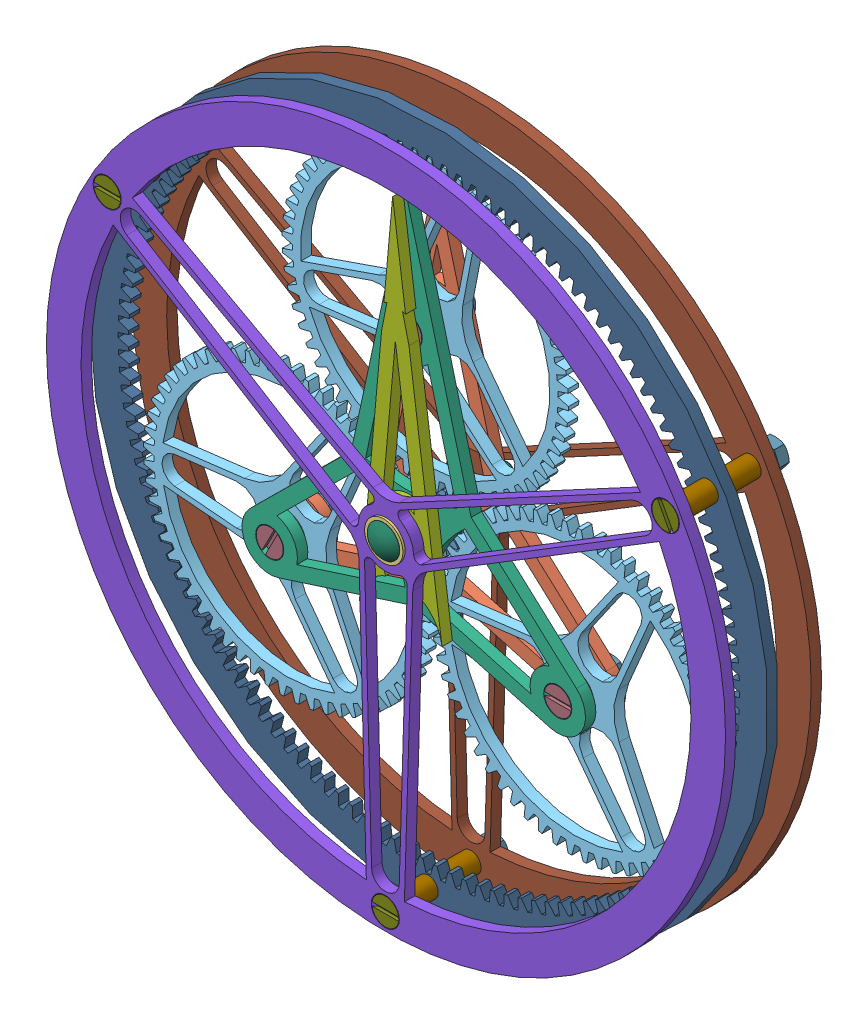
SolidWorks assembly FINAL CLOCK ASSEMBLY, configuration Default. Lengths in mm.
Overall size (311.76 311.76 60.58).
55 component instances, 16 part files, 120 mates.
Components (placement in the parent):
- SUN GEAR - HOUR-1: SUN GEAR - HOUR [Inch - Spur gear 12DP 12T 14.5PA .1875FW ---S12N3.0H2.0L0.25N] at (-10.4963 -0.1494 4.7625) x (0 0 -1) z (-0.958685 -0.284468 0) size (4.76 28.9 28.9)
- HOUR HAND - REAR-1: HOUR HAND - REAR [Default] at (-10.4963 -0.1494 -1.1811) x (-0.021998 0.999758 0) z (0 0 1) size (181.56 157.38 4.76)
- FLANGE BEARING-1: FLANGE BEARING [57155K324] at (-10.4963 -0.1494 -4.4704) size (17.53 17.53 4.98)
- Hi Collar LW 0.25-1: Hi Collar LW 0.25 [Hi Collar LW 0.25] at (-10.4963 -0.1494 -1.9812) x (0 0 -1) z (1 0 0) size (1.98 9.22 9.21)
- PLANET GEAR - HOUR-1: PLANET GEAR - HOUR [Inch - Spur gear 12DP 60T 14.5PA .1875FW ---S60N3.0H2.0L0.625N] at (-75.6334 -39.6919 0) x (0 0 1) z (0.019031 -0.999819 0) size (4.76 131.13 131.13)
- FLANGE BEARING-2: FLANGE BEARING [57155K324] at (-75.6334 -39.6919 3.2893) x (0.381849 -0.924225 0) z (0 0 -1) size (17.53 17.53 4.98)
- Hi Collar LW 0.25-2: Hi Collar LW 0.25 [Hi Collar LW 0.25] at (-75.6334 -39.6919 0.8001) x (0 0 1) z (-1 0 0) size (1.98 9.22 9.21)
- PLANET GEAR - HOUR-2: PLANET GEAR - HOUR [Inch - Spur gear 12DP 60T 14.5PA .1875FW ---S60N3.0H2.0L0.625N] at (-12.1726 76.0322 0) x (0 0 1) z (0.228279 -0.973596 0) size (4.76 131.13 131.13)
- FLANGE BEARING-3: FLANGE BEARING [57155K324] at (-12.1726 76.0322 3.2893) x (0.381849 -0.924225 0) z (0 0 -1) size (17.53 17.53 4.98)
- Hi Collar LW 0.25-3: Hi Collar LW 0.25 [Hi Collar LW 0.25] at (-12.1726 76.0322 0.8001) x (0 0 1) z (-1 0 0) size (1.98 9.22 9.21)
- PLANET GEAR - HOUR-4: PLANET GEAR - HOUR [Inch - Spur gear 12DP 60T 14.5PA .1875FW ---S60N3.0H2.0L0.625N] at (56.317 -36.7885 0) x (0 0 1) z (0.018854 -0.999822 0) size (4.76 131.13 131.13)
- FLANGE BEARING-5: FLANGE BEARING [57155K324] at (56.317 -36.7885 3.2893) x (0.381849 -0.924225 0) z (0 0 -1) size (17.53 17.53 4.98)
- Hi Collar LW 0.25-4: Hi Collar LW 0.25 [Hi Collar LW 0.25] at (56.317 -36.7885 0.8001) x (0 0 1) z (-1 0 0) size (1.98 9.22 9.21)
- HOUR HAND - FRONT-1: HOUR HAND - FRONT [Default] at (-10.4963 -0.1494 12.5222) x (-0.021998 0.999758 0) z (0 0 1) size (181.56 157.38 4.76)
- FLANGE BEARING-6: FLANGE BEARING [57155K324] at (-10.4963 -0.1494 9.2329) size (17.53 17.53 4.98)
- Hi Collar LW 0.25-5: Hi Collar LW 0.25 [Hi Collar LW 0.25] at (-10.4963 -0.1494 6.7437) x (0 0 1) z (-1 0 0) size (1.98 9.22 9.21)
- Hi Collar LW 0.25-6: Hi Collar LW 0.25 [Hi Collar LW 0.25] at (-75.6334 -39.6919 5.7785) x (0 0 -1) z (1 0 0) size (1.98 9.22 9.21)
- Hi Collar LW 0.25-7: Hi Collar LW 0.25 [Hi Collar LW 0.25] at (-12.1726 76.0322 5.7785) x (0 0 -1) z (1 0 0) size (1.98 9.22 9.21)
- Hi Collar LW 0.25-8: Hi Collar LW 0.25 [Hi Collar LW 0.25] at (56.317 -36.7885 5.7785) x (0 0 -1) z (1 0 0) size (1.98 9.22 9.21)
- Hi Collar LW 0.25-9: Hi Collar LW 0.25 [Hi Collar LW 0.25] at (-10.4963 -0.1494 11.7221) x (0 0 -1) z (1 0 0) size (1.98 9.22 9.21)
- MINUTE HAND-1: MINUTE HAND [Default] at (-10.4963 -0.1494 13.7033) x (-0.021988 0.999758 0) z (0 0 -1) size (167.69 37.86 4.76)
- FRONT FRAME-1: FRONT FRAME [Default] at (-10.4963 -0.1494 24.4094) x (-0.999998 0.001964 0) z (0 0 1) size (311.15 311.15 4.76)
- FLANGE BEARING-7: FLANGE BEARING [57155K324] at (-10.4963 -0.1494 22.9362) x (0.923728 0.383049 0) z (0 0 -1) size (17.53 17.53 4.98)
- Hi Collar LW 0.25-10: Hi Collar LW 0.25 [Hi Collar LW 0.25] at (-10.4963 -0.1494 20.447) x (0 0 1) z (-1 0 0) size (1.98 9.22 9.21)
- STAND OFF - FRONT FRAME-1: STAND OFF - FRONT FRAME [Default] at (-10.7863 -147.7866 4.7879) x (0.923728 0.383049 0) z (0 0 -1) size (9.22 9.22 14.86)
- STAND OFF - FRONT FRAME-2: STAND OFF - FRONT FRAME [Default] at (-138.2089 73.9203 4.7879) x (0.923728 0.383049 0) z (0 0 -1) size (9.22 9.22 14.86)
- STAND OFF - FRONT FRAME-3: STAND OFF - FRONT FRAME [Default] at (117.5062 73.4181 4.7879) x (0.923728 0.383049 0) z (0 0 -1) size (9.22 9.22 14.86)
- RING GEAR - HOUR-2: RING GEAR - HOUR [Inch - Internal spur gear 12DP 132T 14.5PA .1875FW ---S132S12.25OD 1.0AF] at (-10.4963 -0.1494 4.7879) x (0 0 -1) z (-0.999998 0.001964 0) size (4.76 311.15 311.15)
- STAND OFF - FRONT FRAME-4: STAND OFF - FRONT FRAME [Default] at (-10.7863 -147.7866 -14.8336) x (-0.923728 -0.383049 0) z (0 0 -1) size (9.22 9.22 14.86)
- STAND OFF - FRONT FRAME-5: STAND OFF - FRONT FRAME [Default] at (-138.2089 73.9203 -14.8336) x (-0.923728 -0.383049 0) z (0 0 -1) size (9.22 9.22 14.86)
- STAND OFF - FRONT FRAME-6: STAND OFF - FRONT FRAME [Default] at (117.5062 73.4181 -14.8336) x (-0.923728 -0.383049 0) z (0 0 -1) size (9.22 9.22 14.86)
- REAR FRAME-1: REAR FRAME [Default] at (-10.4963 -0.1494 -14.8336) x (-0.999998 0.001964 0) z (0 0 1) size (311.15 311.15 4.76)
- STAND OFF - REAR CENTER-1: STAND OFF - REAR CENTER [Default] at (-10.4963 -0.1494 -15.7226) x (-0.923728 -0.383049 0) z (0 0 -1) size (9.22 9.22 8.76)
- FLANGE BEARING-8: FLANGE BEARING [57155K324] at (-10.4963 -0.1494 -18.1229) size (17.53 17.53 4.98)
- CSBOLT 0.2500-20x1x0.75-S-S-2: CSBOLT 0.2500-20x1x0.75-S-S [CSBOLT 0.2500-20x1x0.75-S-S] at (-75.6334 -39.6919 12.5222) x (0 0 -1) z (-0.457415 -0.889253 0) size (25.4 12.32 12.19)
- CSBOLT 0.2500-20x1x0.75-S-S-3: CSBOLT 0.2500-20x1x0.75-S-S [CSBOLT 0.2500-20x1x0.75-S-S] at (-12.1726 76.0322 12.5222) x (0 0 -1) z (0.679081 -0.734063 0) size (25.4 12.32 12.19)
- CSBOLT 0.2500-20x1x0.75-S-S-4: CSBOLT 0.2500-20x1x0.75-S-S [CSBOLT 0.2500-20x1x0.75-S-S] at (56.317 -36.7885 12.5222) x (0 0 -1) z (1 0 0) size (25.4 12.32 12.19)
- Hi Collar LW 0.25-13: Hi Collar LW 0.25 [Hi Collar LW 0.25] at (-12.1726 76.0322 -5.9436) x (0 0 1) z (-1 0 0) size (1.98 9.22 9.21)
- Hi Collar LW 0.25-15: Hi Collar LW 0.25 [Hi Collar LW 0.25] at (-75.6334 -39.6919 -5.9436) x (0 0 1) z (-1 0 0) size (1.98 9.22 9.21)
- Hi Collar LW 0.25-16: Hi Collar LW 0.25 [Hi Collar LW 0.25] at (56.317 -36.7885 -5.9436) x (0 0 1) z (-1 0 0) size (1.98 9.22 9.21)
- MSHXNUT 0.250-20-S-S-3: MSHXNUT 0.250-20-S-S [MSHXNUT 0.250-20-S-S] at (-75.6334 -39.6919 -12.827) x (0.923728 0.383049 0) z (0 0 -1) size (11.13 12.85 4.9)
- MSHXNUT 0.250-20-S-S-4: MSHXNUT 0.250-20-S-S [MSHXNUT 0.250-20-S-S] at (56.317 -36.7885 -12.827) x (0.923728 0.383049 0) z (0 0 -1) size (11.13 12.85 4.9)
- MSHXNUT 0.250-20-S-S-6: MSHXNUT 0.250-20-S-S [MSHXNUT 0.250-20-S-S] at (-12.1726 76.0322 -12.827) x (0.998079 -0.061957 0) z (0 0 -1) size (11.13 12.85 4.9)
- RHBOLT 0.25-20x2.25x.75-S-1: RHBOLT 0.25-20x2.25x.75-S [RHBOLT 0.25-20x2.25x.75-S] at (-10.4963 -0.1494 28.8544) x (0 0 -1) z (0.963038 -0.269365 0) size (60.58 14.71 14.71)
- Hi Collar LW 0.25-17: Hi Collar LW 0.25 [Hi Collar LW 0.25] at (-10.4963 -0.1494 -20.6121) x (0 0 1) z (-1 0 0) size (1.98 9.22 9.21)
- MSHXNUT 0.250-20-S-S-8: MSHXNUT 0.250-20-S-S [MSHXNUT 0.250-20-S-S] at (-10.4963 -0.1494 -27.4955) x (0.923728 0.383049 0) z (0 0 -1) size (11.13 12.85 4.9)
- CSBOLT 0.2500-20x2x0.75-S-S-1: CSBOLT 0.2500-20x2x0.75-S-S [CSBOLT 0.2500-20x2x0.75-S-S] at (-10.7863 -147.7866 24.4094) x (0 0 -1) z (1 0 0) size (50.8 12.32 12.19)
- CSBOLT 0.2500-20x2x0.75-S-S-2: CSBOLT 0.2500-20x2x0.75-S-S [CSBOLT 0.2500-20x2x0.75-S-S] at (117.5062 73.4181 24.4094) x (0 0 -1) z (0.472121 -0.881534 0) size (50.8 12.32 12.19)
- Hi Collar LW 0.25-19: Hi Collar LW 0.25 [Hi Collar LW 0.25] at (-10.7863 -147.7866 -19.5961) x (0 0 1) z (-1 0 0) size (1.98 9.22 9.21)
- MSHXNUT 0.250-20-S-S-9: MSHXNUT 0.250-20-S-S [MSHXNUT 0.250-20-S-S] at (-10.7863 -147.7866 -26.4795) x (0.923728 0.383049 0) z (0 0 -1) size (11.13 12.85 4.9)
- CSBOLT 0.2500-20x2x0.75-S-S-3: CSBOLT 0.2500-20x2x0.75-S-S [CSBOLT 0.2500-20x2x0.75-S-S] at (-138.2089 73.9203 24.4094) x (0 0 -1) z (1 0 0) size (50.8 12.32 12.19)
- Hi Collar LW 0.25-20: Hi Collar LW 0.25 [Hi Collar LW 0.25] at (-138.2089 73.9203 -19.5961) x (0 0 1) z (-1 0 0) size (1.98 9.22 9.21)
- MSHXNUT 0.250-20-S-S-10: MSHXNUT 0.250-20-S-S [MSHXNUT 0.250-20-S-S] at (-138.2089 73.9203 -26.4795) x (0.923728 0.383049 0) z (0 0 -1) size (11.13 12.85 4.9)
- Hi Collar LW 0.25-23: Hi Collar LW 0.25 [Hi Collar LW 0.25] at (117.5062 73.4181 -19.5961) x (0 0 1) z (-1 0 0) size (1.98 9.22 9.21)
- MSHXNUT 0.250-20-S-S-11: MSHXNUT 0.250-20-S-S [MSHXNUT 0.250-20-S-S] at (117.5062 73.4181 -26.4795) x (0.923728 0.383049 0) z (0 0 -1) size (11.13 12.85 4.9)
Mates (geometry in assembly coordinates):
- Coincident1: coincident anti-aligned: plane of SUN GEAR - HOUR-1 through (-10.4963 -0.1494 0) normal (0 0 -1)
- Concentric1: concentric aligned: cylinder of SUN GEAR - HOUR-1 through (-10.4963 -0.1494 -46.0376) axis (0 0 1) radius 3.175; circle of HOUR HAND - REAR-1
- Concentric2: concentric aligned: cylinder of HOUR HAND - REAR-1 through (-10.4963 -0.1494 -5.9436) axis (0 0 1) radius 7.9375; cylinder of FLANGE BEARING-1 through (-10.4963 -0.1494 -1.9812) axis (0 0 1) radius 7.9375
- Coincident3: coincident anti-aligned: plane of HOUR HAND - REAR-1 through (56.317 -36.7885 -5.9436) normal (0 0 -1); plane of FLANGE BEARING-1 through (-10.4963 5.8858 -5.9436) normal (0 0 1)
- Concentric31: concentric anti-aligned: cone of FLANGE BEARING-1 through (-10.4963 -0.1494 -1.9812) axis (0 0 -1); cylinder of Hi Collar LW 0.25-1 through (-10.4963 -0.1494 32.9438) axis (0 0 1) radius 3.302
- Coincident41: coincident anti-aligned: plane of FLANGE BEARING-1 through (-10.4963 4.9279 -1.9812) normal (0 0 1); plane of Hi Collar LW 0.25-1 through (-10.4963 3.1526 -1.9812) normal (0 0 -1)
- Coincident5: coincident anti-aligned: plane of SUN GEAR - HOUR-1 through (-10.4963 -0.1494 0) normal (0 0 -1); plane of Hi Collar LW 0.25-1 through (-10.4963 4.4607 0) normal (0 0 1)
- Concentric4: concentric aligned: cylinder of PLANET GEAR - HOUR-1 through (-75.6334 -39.6919 50.8001) axis (0 0 -1) radius 7.9375; cylinder of FLANGE BEARING-2 through (-75.6334 -39.6919 0.8001) axis (0 0 -1) radius 7.9375
- Coincident6: coincident anti-aligned: plane of PLANET GEAR - HOUR-1 through (-75.6334 -39.6919 4.7625) normal (0 0 1); plane of FLANGE BEARING-2 through (-81.2113 -41.9964 4.7625) normal (0 0 -1)
- Concentric51: concentric aligned: cylinder of FLANGE BEARING-2 through (-75.6334 -39.6919 0.8001) axis (0 0 -1) radius 5.0773; cylinder of Hi Collar LW 0.25-2 through (-75.6334 -39.6919 -34.1249) axis (0 0 -1) radius 3.302
- Coincident71: coincident anti-aligned: plane of FLANGE BEARING-2 through (-80.3259 -41.6306 0.8001) normal (0 0 -1); plane of Hi Collar LW 0.25-2 through (-75.6334 -36.3899 0.8001) normal (0 0 1)
- Coincident8: coincident anti-aligned: plane of HOUR HAND - REAR-1 through (56.317 -36.7885 -1.1811) normal (0 0 1); plane of Hi Collar LW 0.25-2 through (-75.6334 -35.0818 -1.1811) normal (0 0 -1)
- Concentric6: concentric anti-aligned: cylinder of HOUR HAND - REAR-1 through (-75.6334 -39.6919 -1.1811) axis (0 0 1) radius 3.3782; cylinder of FLANGE BEARING-2 through (-75.6334 -39.6919 0.8001) axis (0 0 -1) radius 3.175
- Concentric7: concentric aligned: cylinder of PLANET GEAR - HOUR-2 through (-12.1726 76.0322 50.8001) axis (0 0 -1) radius 7.9375; cylinder of FLANGE BEARING-3 through (-12.1726 76.0322 0.8001) axis (0 0 -1) radius 7.9375
- Coincident9: coincident anti-aligned: plane of PLANET GEAR - HOUR-2 through (-12.1726 76.0322 4.7625) normal (0 0 1); plane of FLANGE BEARING-3 through (-17.7505 73.7276 4.7625) normal (0 0 -1)
- Concentric8: concentric anti-aligned: cylinder of HOUR HAND - REAR-1 through (-12.1726 76.0322 -1.1811) axis (0 0 1) radius 3.3782; cylinder of FLANGE BEARING-3 through (-12.1726 76.0322 0.8001) axis (0 0 -1) radius 3.175
- Concentric91: concentric anti-aligned: cone of FLANGE BEARING-3 through (-12.1726 76.0322 0.8001) axis (0 0 1); cylinder of Hi Collar LW 0.25-3 through (-12.1726 76.0322 -34.1249) axis (0 0 -1) radius 3.302
- Coincident101: coincident anti-aligned: plane of FLANGE BEARING-3 through (-16.8651 74.0934 0.8001) normal (0 0 -1); plane of Hi Collar LW 0.25-3 through (-12.1726 79.3342 0.8001) normal (0 0 1)
- Coincident11: coincident anti-aligned: plane of HOUR HAND - REAR-1 through (56.317 -36.7885 -1.1811) normal (0 0 1); plane of Hi Collar LW 0.25-3 through (-12.1726 80.6423 -1.1811) normal (0 0 -1)
- Concentric11: concentric aligned: cylinder of PLANET GEAR - HOUR-4 through (56.317 -36.7885 50.8001) axis (0 0 -1) radius 7.9375; cylinder of FLANGE BEARING-5 through (56.317 -36.7885 0.8001) axis (0 0 -1) radius 7.9375
- Coincident12: coincident anti-aligned: plane of PLANET GEAR - HOUR-4 through (56.317 -36.7885 4.7625) normal (0 0 1); plane of FLANGE BEARING-5 through (50.7391 -39.0931 4.7625) normal (0 0 -1)
- Concentric12: concentric anti-aligned: cylinder of HOUR HAND - REAR-1 through (56.317 -36.7885 -1.1811) axis (0 0 1) radius 3.3782; cylinder of FLANGE BEARING-5 through (56.317 -36.7885 0.8001) axis (0 0 -1) radius 3.175
- Concentric131: concentric aligned: cylinder of FLANGE BEARING-5 through (56.317 -36.7885 0.8001) axis (0 0 -1) radius 5.0773; cylinder of Hi Collar LW 0.25-4 through (56.317 -36.7885 -34.1249) axis (0 0 -1) radius 3.302
- Coincident131: coincident anti-aligned: plane of FLANGE BEARING-5 through (51.6244 -38.7273 0.8001) normal (0 0 -1); plane of Hi Collar LW 0.25-4 through (56.317 -33.4865 0.8001) normal (0 0 1)
- Coincident14: coincident anti-aligned: plane of HOUR HAND - REAR-1 through (56.317 -36.7885 -1.1811) normal (0 0 1); plane of Hi Collar LW 0.25-4 through (56.317 -32.1784 -1.1811) normal (0 0 -1)
- Concentric14: concentric aligned: cylinder of HOUR HAND - FRONT-1 through (-10.4963 -0.1494 7.7597) axis (0 0 1) radius 7.9375; cylinder of FLANGE BEARING-6 through (-10.4963 -0.1494 11.7221) axis (0 0 1) radius 7.9375
- Coincident15: coincident anti-aligned: plane of HOUR HAND - FRONT-1 through (56.317 -36.7885 7.7597) normal (0 0 -1); plane of FLANGE BEARING-6 through (-10.4963 5.8858 7.7597) normal (0 0 1)
- Concentric151: concentric anti-aligned: cone of FLANGE BEARING-6 through (-10.4963 -0.1494 6.9926) axis (0 0 1); cylinder of Hi Collar LW 0.25-5 through (-10.4963 -0.1494 -28.1813) axis (0 0 -1) radius 3.302
- Coincident161: coincident anti-aligned: plane of FLANGE BEARING-6 through (-10.4963 3.2745 6.7437) normal (0 0 -1); plane of Hi Collar LW 0.25-5 through (-10.4963 3.1526 6.7437) normal (0 0 1)
- Concentric161: concentric anti-aligned: cone of FLANGE BEARING-2 through (-75.6334 -39.6919 5.5296) axis (0 0 -1); cylinder of Hi Collar LW 0.25-6 through (-75.6334 -39.6919 40.7035) axis (0 0 1) radius 3.302
- Coincident171: coincident anti-aligned: plane of FLANGE BEARING-2 through (-78.7978 -40.9993 5.7785) normal (0 0 1); plane of Hi Collar LW 0.25-6 through (-75.6334 -36.3899 5.7785) normal (0 0 -1)
- Concentric171: concentric anti-aligned: cylinder of FLANGE BEARING-3 through (-12.1726 76.0322 0.8001) axis (0 0 -1) radius 5.0773; cylinder of Hi Collar LW 0.25-7 through (-12.1726 76.0322 40.7035) axis (0 0 1) radius 3.302
- Coincident181: coincident anti-aligned: plane of FLANGE BEARING-3 through (-15.337 74.7247 5.7785) normal (0 0 1); plane of Hi Collar LW 0.25-7 through (-12.1726 79.3342 5.7785) normal (0 0 -1)
- Concentric181: concentric anti-aligned: cone of FLANGE BEARING-5 through (56.317 -36.7885 5.5296) axis (0 0 -1); cylinder of Hi Collar LW 0.25-8 through (56.317 -36.7885 40.7035) axis (0 0 1) radius 3.302
- Coincident191: coincident anti-aligned: plane of FLANGE BEARING-5 through (53.1525 -38.0959 5.7785) normal (0 0 1); plane of Hi Collar LW 0.25-8 through (56.317 -33.4865 5.7785) normal (0 0 -1)
- Coincident20: coincident anti-aligned: plane of SUN GEAR - HOUR-1 through (-10.4963 -0.1494 4.7625) normal (0 0 1); plane of Hi Collar LW 0.25-5 through (-10.4963 4.4607 4.7625) normal (0 0 -1)
- Concentric19: concentric aligned: cylinder of HOUR HAND - REAR-1 through (-12.1726 76.0322 -1.1811) axis (0 0 1) radius 3.3782; cylinder of HOUR HAND - FRONT-1 through (-12.1726 76.0322 12.5222) axis (0 0 1) radius 3.3782
- Concentric20: concentric aligned: cylinder of HOUR HAND - REAR-1 through (-75.6334 -39.6919 -1.1811) axis (0 0 1) radius 3.3782; cylinder of HOUR HAND - FRONT-1 through (-75.6334 -39.6919 12.5222) axis (0 0 1) radius 3.3782
- Concentric21: concentric aligned: cylinder of HOUR HAND - REAR-1 through (56.317 -36.7885 -1.1811) axis (0 0 1) radius 3.3782; cylinder of HOUR HAND - FRONT-1 through (56.317 -36.7885 12.5222) axis (0 0 1) radius 3.3782
- Concentric221: concentric anti-aligned: cone of FLANGE BEARING-6 through (-10.4963 -0.1494 11.7221) axis (0 0 -1); cylinder of Hi Collar LW 0.25-9 through (-10.4963 -0.1494 46.6471) axis (0 0 1) radius 3.302
- Coincident211: coincident anti-aligned: plane of FLANGE BEARING-6 through (-10.4963 4.9279 11.7221) normal (0 0 1); plane of Hi Collar LW 0.25-9 through (-10.4963 3.1526 11.7221) normal (0 0 -1)
- Coincident22: coincident anti-aligned: plane of Hi Collar LW 0.25-9 through (-10.4963 4.4607 13.7033) normal (0 0 1); plane of MINUTE HAND-1 through (-9.6586 -38.2402 13.7033) normal (0 0 -1)
- Concentric23: concentric anti-aligned: cylinder of FLANGE BEARING-6 through (-10.4963 -0.1494 11.7221) axis (0 0 1) radius 3.175; cylinder of MINUTE HAND-1 through (-10.4963 -0.1494 18.4658) axis (0 0 -1) radius 3.175
- Concentric24: concentric anti-aligned: cylinder of FRONT FRAME-1 through (-10.4963 -0.1494 19.6469) axis (0 0 1) radius 7.9375; cylinder of FLANGE BEARING-7 through (-10.4963 -0.1494 20.447) axis (0 0 -1) radius 7.9375
- Coincident23: coincident anti-aligned: plane of FRONT FRAME-1 through (-10.4963 -0.1494 24.4094) normal (0 0 1); plane of FLANGE BEARING-7 through (-8.1845 -5.7243 24.4094) normal (0 0 -1)
- Concentric251: concentric anti-aligned: cone of FLANGE BEARING-7 through (-10.4963 -0.1494 20.447) axis (0 0 1); cylinder of Hi Collar LW 0.25-10 through (-10.4963 -0.1494 -14.478) axis (0 0 -1) radius 3.302
- Coincident241: coincident anti-aligned: plane of FLANGE BEARING-7 through (-8.5515 -4.8394 20.447) normal (0 0 -1); plane of Hi Collar LW 0.25-10 through (-10.4963 3.1526 20.447) normal (0 0 1)
- Coincident25: coincident anti-aligned: plane of MINUTE HAND-1 through (-9.6586 -38.2402 18.4658) normal (0 0 1); plane of Hi Collar LW 0.25-10 through (-10.4963 4.4607 18.4658) normal (0 0 -1)
- Concentric26: concentric aligned: cylinder of MINUTE HAND-1 through (-10.4963 -0.1494 18.4658) axis (0 0 -1) radius 3.175; cylinder of FLANGE BEARING-7 through (-10.4963 -0.1494 20.447) axis (0 0 -1) radius 3.175
- Concentric27: concentric anti-aligned: cylinder of FRONT FRAME-1 through (-10.7863 -147.7866 24.4094) axis (0 0 1) radius 3.3782; cylinder of STAND OFF - FRONT FRAME-1 through (-10.7863 -147.7866 4.7879) axis (0 0 -1) radius 3.3782
- Coincident26: coincident anti-aligned: plane of FRONT FRAME-1 through (-10.4963 -0.1494 19.6469) normal (0 0 -1); plane of STAND OFF - FRONT FRAME-1 through (-10.7863 -147.7866 19.6469) normal (0 0 1)
- Concentric28: concentric anti-aligned: cylinder of FRONT FRAME-1 through (-138.2089 73.9203 24.4094) axis (0 0 1) radius 3.3782; cylinder of STAND OFF - FRONT FRAME-2 through (-138.2089 73.9203 4.7879) axis (0 0 -1) radius 3.3782
- Coincident27: coincident anti-aligned: plane of FRONT FRAME-1 through (-10.4963 -0.1494 19.6469) normal (0 0 -1); plane of STAND OFF - FRONT FRAME-2 through (-138.2089 73.9203 19.6469) normal (0 0 1)
- Concentric29: concentric anti-aligned: cylinder of FRONT FRAME-1 through (117.5062 73.4181 24.4094) axis (0 0 1) radius 3.3782; cylinder of STAND OFF - FRONT FRAME-3 through (117.5062 73.4181 4.7879) axis (0 0 -1) radius 3.3782
- Coincident28: coincident anti-aligned: plane of FRONT FRAME-1 through (-10.4963 -0.1494 19.6469) normal (0 0 -1); plane of STAND OFF - FRONT FRAME-3 through (117.5062 73.4181 19.6469) normal (0 0 1)
- Concentric31: concentric aligned: cylinder of STAND OFF - FRONT FRAME-1 through (-10.7863 -147.7866 4.7879) axis (0 0 -1) radius 3.3782; cylinder of RING GEAR - HOUR-2 through (-10.7863 -147.7866 0.0254) axis (0 0 -1) radius 3.3782
- Coincident30: coincident anti-aligned: plane of STAND OFF - FRONT FRAME-1 through (-10.7863 -147.7866 4.7879) normal (0 0 -1); plane of RING GEAR - HOUR-2 through (127.0867 -0.4196 4.7879) normal (0 0 1)
- Concentric32: concentric aligned: cylinder of STAND OFF - FRONT FRAME-2 through (-138.2089 73.9203 4.7879) axis (0 0 -1) radius 3.3782; cylinder of RING GEAR - HOUR-2 through (-138.2089 73.9203 0.0254) axis (0 0 -1) radius 3.3782
- Concentric33: concentric aligned: cylinder of STAND OFF - FRONT FRAME-3 through (117.5062 73.4181 4.7879) axis (0 0 -1) radius 3.3782; cylinder of RING GEAR - HOUR-2 through (117.5062 73.4181 0.0254) axis (0 0 -1) radius 3.3782
- Coincident31: coincident anti-aligned: plane of RING GEAR - HOUR-2 through (127.0867 -0.4196 0.0254) normal (0 0 -1); plane of STAND OFF - FRONT FRAME-4 through (-10.7863 -147.7866 0.0254) normal (0 0 1)
- Concentric34: concentric aligned: cylinder of RING GEAR - HOUR-2 through (-10.7863 -147.7866 0.0254) axis (0 0 -1) radius 3.3782; cylinder of STAND OFF - FRONT FRAME-4 through (-10.7863 -147.7866 -14.8336) axis (0 0 -1) radius 3.3782
- Coincident32: coincident anti-aligned: plane of RING GEAR - HOUR-2 through (127.0867 -0.4196 0.0254) normal (0 0 -1); plane of STAND OFF - FRONT FRAME-5 through (-138.2089 73.9203 0.0254) normal (0 0 1)
- Concentric35: concentric aligned: cylinder of RING GEAR - HOUR-2 through (-138.2089 73.9203 0.0254) axis (0 0 -1) radius 3.3782; cylinder of STAND OFF - FRONT FRAME-5 through (-138.2089 73.9203 -14.8336) axis (0 0 -1) radius 3.3782
- Coincident33: coincident anti-aligned: plane of RING GEAR - HOUR-2 through (127.0867 -0.4196 0.0254) normal (0 0 -1); plane of STAND OFF - FRONT FRAME-6 through (117.5062 73.4181 0.0254) normal (0 0 1)
- Concentric36: concentric aligned: cylinder of RING GEAR - HOUR-2 through (117.5062 73.4181 0.0254) axis (0 0 -1) radius 3.3782; cylinder of STAND OFF - FRONT FRAME-6 through (117.5062 73.4181 -14.8336) axis (0 0 -1) radius 3.3782
- Coincident34: coincident anti-aligned: plane of FLANGE BEARING-1 through (-10.4963 3.2745 -6.9596) normal (0 0 -1); plane of STAND OFF - REAR CENTER-1 through (-10.4963 -0.1494 -6.9596) normal (0 0 1)
- Concentric37: concentric anti-aligned: cylinder of FLANGE BEARING-1 through (-10.4963 -0.1494 -1.9812) axis (0 0 1) radius 3.175; cylinder of STAND OFF - REAR CENTER-1 through (-10.4963 -0.1494 -15.7226) axis (0 0 -1) radius 3.3782
- Concentric38: concentric aligned: cylinder of REAR FRAME-1 through (-10.4963 -0.1494 -19.5961) axis (0 0 1) radius 7.9375; cylinder of FLANGE BEARING-8 through (-10.4963 -0.1494 -15.6337) axis (0 0 1) radius 7.9375
- Coincident35: coincident anti-aligned: plane of REAR FRAME-1 through (-10.4963 -0.1494 -19.5961) normal (0 0 -1); plane of FLANGE BEARING-8 through (-10.4963 5.8858 -19.5961) normal (0 0 1)
- Concentric39: concentric anti-aligned: cylinder of STAND OFF - FRONT FRAME-4 through (-10.7863 -147.7866 -14.8336) axis (0 0 -1) radius 3.3782; cylinder of REAR FRAME-1 through (-10.7863 -147.7866 -14.8336) axis (0 0 1) radius 3.3782
- Concentric40: concentric anti-aligned: cylinder of STAND OFF - FRONT FRAME-6 through (117.5062 73.4181 -14.8336) axis (0 0 -1) radius 3.3782; cylinder of REAR FRAME-1 through (117.5062 73.4181 -14.8336) axis (0 0 1) radius 3.3782
- Concentric41: concentric anti-aligned: cylinder of STAND OFF - FRONT FRAME-5 through (-138.2089 73.9203 -14.8336) axis (0 0 -1) radius 3.3782; cylinder of REAR FRAME-1 through (-138.2089 73.9203 -14.8336) axis (0 0 1) radius 3.3782
- Coincident36: coincident anti-aligned: plane of STAND OFF - FRONT FRAME-4 through (-10.7863 -147.7866 -14.8336) normal (0 0 -1); plane of REAR FRAME-1 through (-10.4963 -0.1494 -14.8336) normal (0 0 1)
- Concentric421: concentric aligned: cone of HOUR HAND - FRONT-1 through (-75.6334 -39.6919 12.5222) axis (0 0 -1); cone of CSBOLT 0.2500-20x1x0.75-S-S-2 through (-75.6334 -39.6919 12.3995) axis (0 0 -1)
- Coincident37: coincident aligned: plane of HOUR HAND - FRONT-1 through (56.317 -36.7885 12.5222) normal (0 0 1); plane of CSBOLT 0.2500-20x1x0.75-S-S-2 through (-75.6334 -39.6919 12.5222) normal (0 0 1)
- Concentric431: concentric aligned: cone of HOUR HAND - FRONT-1 through (-12.1726 76.0322 12.5222) axis (0 0 -1); cone of CSBOLT 0.2500-20x1x0.75-S-S-3 through (-12.1726 76.0322 12.3995) axis (0 0 -1)
- Coincident38: coincident aligned: plane of HOUR HAND - FRONT-1 through (56.317 -36.7885 12.5222) normal (0 0 1); plane of CSBOLT 0.2500-20x1x0.75-S-S-3 through (-12.1726 76.0322 12.5222) normal (0 0 1)
- Concentric451: concentric aligned: cone of HOUR HAND - FRONT-1 through (56.317 -36.7885 12.5222) axis (0 0 -1); cone of CSBOLT 0.2500-20x1x0.75-S-S-4 through (56.317 -36.7885 12.3995) axis (0 0 -1)
- Coincident39: coincident aligned: plane of HOUR HAND - FRONT-1 through (56.317 -36.7885 12.5222) normal (0 0 1); plane of CSBOLT 0.2500-20x1x0.75-S-S-4 through (56.317 -36.7885 12.5222) normal (0 0 1)
- Concentric471: concentric anti-aligned: cylinder of HOUR HAND - REAR-1 through (-12.1726 76.0322 -1.1811) axis (0 0 1) radius 3.3782; cylinder of Hi Collar LW 0.25-13 through (-12.1726 76.0322 -40.8686) axis (0 0 -1) radius 3.302
- Coincident411: coincident anti-aligned: plane of HOUR HAND - REAR-1 through (56.317 -36.7885 -5.9436) normal (0 0 -1); plane of Hi Collar LW 0.25-13 through (-12.1726 79.3342 -5.9436) normal (0 0 1)
- Concentric481: concentric anti-aligned: cylinder of HOUR HAND - REAR-1 through (-75.6334 -39.6919 -1.1811) axis (0 0 1) radius 3.3782; cylinder of Hi Collar LW 0.25-15 through (-75.6334 -39.6919 -40.8686) axis (0 0 -1) radius 3.302
- Coincident421: coincident anti-aligned: plane of HOUR HAND - REAR-1 through (56.317 -36.7885 -5.9436) normal (0 0 -1); plane of Hi Collar LW 0.25-15 through (-75.6334 -36.3899 -5.9436) normal (0 0 1)
- Concentric491: concentric anti-aligned: cylinder of HOUR HAND - REAR-1 through (56.317 -36.7885 -1.1811) axis (0 0 1) radius 3.3782; cylinder of Hi Collar LW 0.25-16 through (56.317 -36.7885 -40.8686) axis (0 0 -1) radius 3.302
- Coincident431: coincident anti-aligned: plane of HOUR HAND - REAR-1 through (56.317 -36.7885 -5.9436) normal (0 0 -1); plane of Hi Collar LW 0.25-16 through (56.317 -33.4865 -5.9436) normal (0 0 1)
- Concentric501: concentric aligned: cylinder of Hi Collar LW 0.25-15 through (-75.6334 -39.6919 -40.8686) axis (0 0 -1) radius 3.302; cylinder of MSHXNUT 0.250-20-S-S-3 through (-75.6334 -39.6919 12.2105) axis (0 0 -1) radius 3.175
- Coincident441: coincident anti-aligned: plane of Hi Collar LW 0.25-15 through (-75.6334 -35.0818 -7.9248) normal (0 0 -1); plane of MSHXNUT 0.250-20-S-S-3 through (-73.173 -45.6251 -7.9248) normal (0 0 1)
- Concentric511: concentric aligned: cylinder of Hi Collar LW 0.25-16 through (56.317 -36.7885 -40.8686) axis (0 0 -1) radius 3.302; cylinder of MSHXNUT 0.250-20-S-S-4 through (56.317 -36.7885 12.2105) axis (0 0 -1) radius 3.175
- Coincident451: coincident anti-aligned: plane of Hi Collar LW 0.25-16 through (56.317 -32.1784 -7.9248) normal (0 0 -1); plane of MSHXNUT 0.250-20-S-S-4 through (58.7773 -42.7217 -7.9248) normal (0 0 1)
- Concentric521: concentric aligned: cylinder of Hi Collar LW 0.25-13 through (-12.1726 76.0322 -40.8686) axis (0 0 -1) radius 3.302; cylinder of MSHXNUT 0.250-20-S-S-6 through (-12.1726 76.0322 12.2105) axis (0 0 -1) radius 3.175
- Coincident461: coincident anti-aligned: plane of Hi Collar LW 0.25-13 through (-12.1726 80.6423 -7.9248) normal (0 0 -1); plane of MSHXNUT 0.250-20-S-S-6 through (-12.5705 69.6214 -7.9248) normal (0 0 1)
- Concentric531: concentric aligned: cylinder of FLANGE BEARING-7 through (-10.4963 -0.1494 25.4254) axis (0 0 1) radius 8.763; cylinder of RHBOLT 0.25-20x2.25x.75-S-1 through (-10.4963 -0.1494 28.8544) axis (0 0 1) radius 7.3533
- Coincident471: coincident anti-aligned: plane of FLANGE BEARING-7 through (-7.5512 -7.2516 25.4254) normal (0 0 1); plane of RHBOLT 0.25-20x2.25x.75-S-1 through (-8.5156 6.9321 25.4254) normal (0 0 -1)
- Concentric541: concentric anti-aligned: cone of FLANGE BEARING-8 through (-10.4963 -0.1494 -20.3632) axis (0 0 1); cylinder of Hi Collar LW 0.25-17 through (-10.4963 -0.1494 -55.5371) axis (0 0 -1) radius 3.302
- Coincident481: coincident anti-aligned: plane of FLANGE BEARING-8 through (-10.4963 3.2745 -20.6121) normal (0 0 -1); plane of Hi Collar LW 0.25-17 through (-10.4963 3.1526 -20.6121) normal (0 0 1)
- Concentric561: concentric aligned: cylinder of Hi Collar LW 0.25-17 through (-10.4963 -0.1494 -55.5371) axis (0 0 -1) radius 3.302; cylinder of MSHXNUT 0.250-20-S-S-8 through (-10.4963 -0.1494 -2.458) axis (0 0 -1) radius 3.175
- Coincident501: coincident anti-aligned: plane of Hi Collar LW 0.25-17 through (-10.4963 4.4607 -22.5933) normal (0 0 -1); plane of MSHXNUT 0.250-20-S-S-8 through (-8.0359 -6.0826 -22.5933) normal (0 0 1)
- Concentric581: concentric aligned: cone of FRONT FRAME-1 through (-10.7863 -147.7866 24.4094) axis (0 0 -1); cone of CSBOLT 0.2500-20x2x0.75-S-S-1 through (-10.7863 -147.7866 24.2867) axis (0 0 -1)
- Coincident51: coincident aligned: plane of FRONT FRAME-1 through (-10.4963 -0.1494 24.4094) normal (0 0 1); plane of CSBOLT 0.2500-20x2x0.75-S-S-1 through (-10.7863 -147.7866 24.4094) normal (0 0 1)
- Concentric591: concentric aligned: cone of FRONT FRAME-1 through (117.5062 73.4181 24.4094) axis (0 0 -1); cone of CSBOLT 0.2500-20x2x0.75-S-S-2 through (117.5062 73.4181 24.2867) axis (0 0 -1)
- Coincident52: coincident aligned: plane of FRONT FRAME-1 through (-10.4963 -0.1494 24.4094) normal (0 0 1); plane of CSBOLT 0.2500-20x2x0.75-S-S-2 through (117.5062 73.4181 24.4094) normal (0 0 1)
- Concentric601: concentric anti-aligned: cylinder of REAR FRAME-1 through (-10.7863 -147.7866 -14.8336) axis (0 0 1) radius 3.3782; cylinder of Hi Collar LW 0.25-19 through (-10.7863 -147.7866 -54.5211) axis (0 0 -1) radius 3.302
- Coincident531: coincident anti-aligned: plane of REAR FRAME-1 through (-10.4963 -0.1494 -19.5961) normal (0 0 -1); plane of Hi Collar LW 0.25-19 through (-10.7863 -144.4846 -19.5961) normal (0 0 1)
- Concentric611: concentric aligned: cylinder of Hi Collar LW 0.25-19 through (-10.7863 -147.7866 -54.5211) axis (0 0 -1) radius 4.6101; cylinder of MSHXNUT 0.250-20-S-S-9 through (-10.7863 -147.7866 -1.442) axis (0 0 -1) radius 3.175
- Coincident541: coincident anti-aligned: plane of Hi Collar LW 0.25-19 through (-10.7863 -143.1765 -21.5773) normal (0 0 -1); plane of MSHXNUT 0.250-20-S-S-9 through (-8.3259 -153.7199 -21.5773) normal (0 0 1)
- Concentric621: concentric aligned: cone of FRONT FRAME-1 through (-138.2089 73.9203 24.4094) axis (0 0 -1); cone of CSBOLT 0.2500-20x2x0.75-S-S-3 through (-138.2089 73.9203 24.2867) axis (0 0 -1)
- Coincident55: coincident aligned: plane of FRONT FRAME-1 through (-10.4963 -0.1494 24.4094) normal (0 0 1); plane of CSBOLT 0.2500-20x2x0.75-S-S-3 through (-138.2089 73.9203 24.4094) normal (0 0 1)
- Concentric631: concentric anti-aligned: cylinder of REAR FRAME-1 through (-138.2089 73.9203 -14.8336) axis (0 0 1) radius 3.3782; cylinder of Hi Collar LW 0.25-20 through (-138.2089 73.9203 -54.5211) axis (0 0 -1) radius 3.302
- Coincident561: coincident anti-aligned: plane of REAR FRAME-1 through (-10.4963 -0.1494 -19.5961) normal (0 0 -1); plane of Hi Collar LW 0.25-20 through (-138.2089 77.2223 -19.5961) normal (0 0 1)
- Concentric641: concentric aligned: cylinder of Hi Collar LW 0.25-20 through (-138.2089 73.9203 -54.5211) axis (0 0 -1) radius 3.302; cylinder of MSHXNUT 0.250-20-S-S-10 through (-138.2089 73.9203 -1.442) axis (0 0 -1) radius 3.175
- Coincident571: coincident anti-aligned: plane of Hi Collar LW 0.25-20 through (-138.2089 78.5304 -21.5773) normal (0 0 -1); plane of MSHXNUT 0.250-20-S-S-10 through (-135.7485 67.9871 -21.5773) normal (0 0 1)
- Concentric651: concentric anti-aligned: cylinder of REAR FRAME-1 through (117.5062 73.4181 -14.8336) axis (0 0 1) radius 3.3782; cylinder of Hi Collar LW 0.25-23 through (117.5062 73.4181 -54.5211) axis (0 0 -1) radius 3.302
- Coincident581: coincident anti-aligned: plane of REAR FRAME-1 through (-10.4963 -0.1494 -19.5961) normal (0 0 -1); plane of Hi Collar LW 0.25-23 through (117.5062 76.7201 -19.5961) normal (0 0 1)
- Concentric661: concentric aligned: cylinder of Hi Collar LW 0.25-23 through (117.5062 73.4181 -54.5211) axis (0 0 -1) radius 4.6101; cylinder of MSHXNUT 0.250-20-S-S-11 through (117.5062 73.4181 -1.442) axis (0 0 -1) radius 3.175
- Coincident591: coincident anti-aligned: plane of Hi Collar LW 0.25-23 through (117.5062 78.0282 -21.5773) normal (0 0 -1); plane of MSHXNUT 0.250-20-S-S-11 through (119.9666 67.4848 -21.5773) normal (0 0 1)
- GearMate1: gear = 55.88 : 25.4 mm: cylinder of PLANET GEAR - HOUR-2 through (-12.1726 76.0322 -10) axis (0 0 -1) radius 65.6167; cylinder of RING GEAR - HOUR-2 through (-10.4963 -0.1494 0.0254) axis (0 0 1) radius 142.3471
- GearMate2: gear = 25.4 : 127 mm: cylinder of PLANET GEAR - HOUR-2 through (-12.1726 76.0322 4.7625) axis (0 0 -1) radius 60.8529; cylinder of SUN GEAR - HOUR-1 through (-10.4963 -0.1494 14.7625) axis (0 0 1) radius 14.8167
- GearMate3: gear = 127 : 25.4 mm: cylinder of SUN GEAR - HOUR-1 through (-10.4963 -0.1494 14.7625) axis (0 0 1) radius 14.8167; cylinder of PLANET GEAR - HOUR-1 through (-75.6334 -39.6919 4.7625) axis (0 0 -1) radius 60.8529
- GearMate4: gear = 127 : 25.4 mm: cylinder of SUN GEAR - HOUR-1 through (-10.4963 -0.1494 14.7625) axis (0 0 1) radius 14.8167; cylinder of PLANET GEAR - HOUR-4 through (56.317 -36.7885 4.7625) axis (0 0 -1) radius 60.8529
- Lock2: lock: unknown of SUN GEAR - HOUR-1; unknown of MINUTE HAND-1
